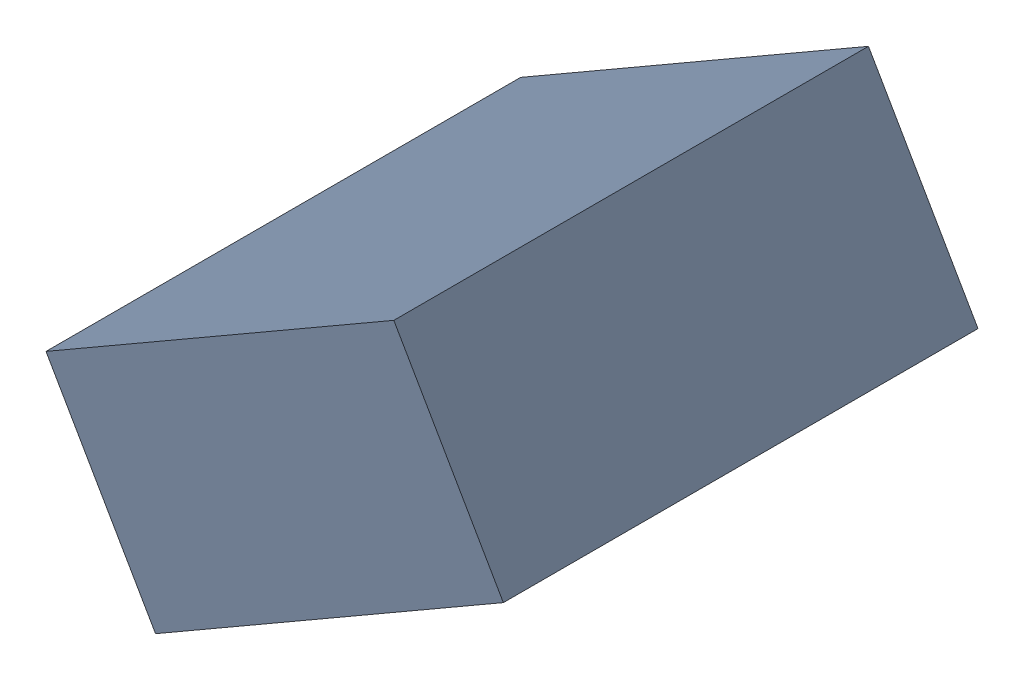
SolidWorks assembly C30_TDA2, configuration Standard. Lengths in mm.
Overall size (1.25 1.07 1.3).
2 component instances, 1 part files, 0 mates.
Components (placement in the parent):
- 885542920-1: 885542920 [Standard] at (51.5598 27.8511 0) size (1.25 1.07 1.3)
  - Extruded_24-1: Extruded_24 [Standard] at origin size (1.25 1.07 1.3)
